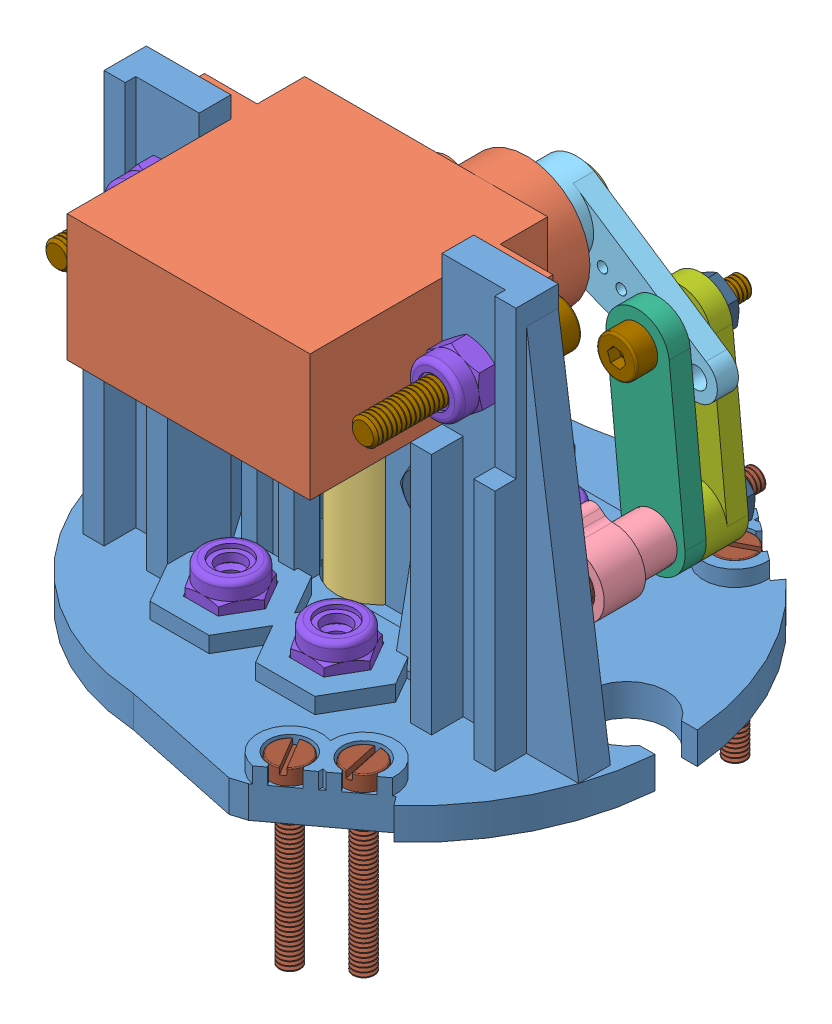
SolidWorks assembly Rückseite, configuration Standard. Lengths in mm.
Overall size (49.92 53 48.18).
28 component instances, 12 part files, 62 mates.
Components (placement in the parent):
- Backside-1: Backside [Standard] at (-0.7502 -6.4244 50) size (49.92 40 48.18)
- servo-1: servo [Standard] at (-9.7502 31.5756 70.5) x (1 0 0) z (0 1 0) size (33 29.25 12)
- Druecker-1: Druecker [Standard] at (-0.7502 16.2056 50) x (1 0 0) z (0 0 -1) size (7.5 32 7.5)
- Hebel-1: Hebel [Standard] at (9.2498 10.5756 50.9) x (0.999716 0.023826 0) z (0 0 -1) size (27.06 14 7.65)
- Servo-Arm-1: Servo-Arm [Standard] at (7.2498 25.5756 39.25) x (0.887861 -0.460111 0) z (-0.460111 -0.887861 0) size (20.6 4.3 7.2)
- Hebel2-1: Hebel2 [Standard] at (18.5142 5.5894 41.25) x (-0.099863 0.995001 0) z (0.995001 0.099863 0) size (21 2 6)
- Hebel2-Double-1: Hebel2-Double [Standard] at (18.5142 5.5894 39.25) x (-0.099863 0.995001 0) z (-0.995001 -0.099863 0) size (21 4 6)
- User Library-Mutter DIN-985_-1: User Library-Mutter DIN-985_ [Mutter DIN-985 M3-A2] at (-4.7502 -3.4244 60) x (0 1 0) z (0 0 1) size (4 6.35 5.5)
- User Library-Mutter DIN-985_-2: User Library-Mutter DIN-985_ [Mutter DIN-985 M3-A2] at (5.2498 -3.4244 60) x (0 1 0) z (-0.866025 0 0.5) size (4 6.35 5.5)
- User Library-Mutter DIN-985_-3: User Library-Mutter DIN-985_ [Mutter DIN-985 M3-A2] at (5.2498 -3.4244 40) x (0 1 0) z (-0.866025 0 -0.5) size (4 6.35 5.5)
- User Library-Mutter DIN-985_-4: User Library-Mutter DIN-985_ [Mutter DIN-985 M3-A2] at (-4.7502 -3.4244 40) x (0 1 0) z (-0.866025 0 0.5) size (4 6.35 5.5)
- socket head cap screw 4762_din-1: socket head cap screw 4762_din [ISO 4762 M2 x 10 --- 10S] at (9.2498 10.5756 43.8) x (0 0 1) z (0.327477 -0.944859 0) size (12 3.8 3.8)
- socket head cap screw 4762_din-2: socket head cap screw 4762_din [ISO 4762 M2 x 10 --- 10S] at (-0.7502 12.2056 55.25) x (0 0 -1) z (0.060223 0.998185 0) size (12 3.8 3.8)
- socket head cap screw 4762_din-3: socket head cap screw 4762_din [ISO 4762 M2 x 10 --- 10S] at (17.0163 20.5144 45.25) x (0 0 -1) z (0.77119 -0.636606 0) size (12 3.8 3.8)
- nut__style_1__m2x0_4__ansi_b18_2_4_1m-1: nut__style_1__m2x0_4__ansi_b18_2_4_1m [Default] at (-0.7502 12.2056 46.75) x (0.866025 -0.5 0) z (0 0 -1) size (4.62 4 1.6)
- nut__style_1__m2x0_4__ansi_b18_2_4_1m-2: nut__style_1__m2x0_4__ansi_b18_2_4_1m [Default] at (17.0163 20.5144 35.65) x (-0.849495 0.527596 0) z (0 0 1) size (4.62 4 1.6)
- nut__style_1__m2x0_4__ansi_b18_2_4_1m-3: nut__style_1__m2x0_4__ansi_b18_2_4_1m [Default] at (9.2498 10.5756 54.2) x (0.532315 -0.846547 0) z (0 0 1) size (4.62 4 1.6)
- User Library-Mutter DIN-985_-5: User Library-Mutter DIN-985_ [Mutter DIN-985 M2,5-A2] at (-12.7502 25.5756 58) x (0 0 1) z (-0.937505 -0.347973 0) size (3.8 5.77 5)
- User Library-Mutter DIN-985_-6: User Library-Mutter DIN-985_ [Mutter DIN-985 M2,5-A2] at (16.2498 25.5756 58) x (0 0 1) z (-0.395566 -0.918438 0) size (3.8 5.77 5)
- slotted cheese head screw_din-1: slotted cheese head screw_din [ISO 1207 - M2 x 16 --- 16S] at (11.3929 -2.0244 70.5635) x (0 -1 0) z (0.511563 0 0.859246) size (17.41 3.8 3.8)
- slotted cheese head screw_din-2: slotted cheese head screw_din [ISO 1207 - M2 x 16 --- 16S] at (11.3929 -2.0244 29.4365) x (0 -1 0) z (-0.876101 0 0.482128) size (17.41 3.8 3.8)
- slotted cheese head screw_din-3: slotted cheese head screw_din [ISO 1207 - M2 x 16 --- 16S] at (15.4084 -2.0244 32.4156) x (0 -1 0) z (-0.890448 0 0.455085) size (17.41 3.8 3.8)
- slotted cheese head screw_din-4: slotted cheese head screw_din [ISO 1207 - M2 x 16 --- 16S] at (15.4084 -2.0244 67.5844) x (0 -1 0) z (0.212665 0 0.977125) size (17.41 3.8 3.8)
- slotted cheese head screw_din-5: slotted cheese head screw_din [ISO 1207 - M2 x 16 --- 16S] at (18.5142 5.5894 50.85) x (0 0 -1) z (0.559209 -0.829027 0) size (17.41 3.8 3.8)
- nut__style_1__m2x0_4__ansi_b18_2_4_1m-4: nut__style_1__m2x0_4__ansi_b18_2_4_1m [Default] at (18.5142 5.5894 37.25) x (-0.800931 0.598757 0) z (0 0 -1) size (4.62 4 1.6)
- cross fh tapping 7976_din-2: cross fh tapping 7976_din [Tapping screw DIN 7982-ST2.9x6.5-C-Z-S] at (7.2498 25.5756 38.5) x (0 0 1) z (-0.95506 0.296413 0) size (6.51 5.5 5.5)
- socket head cap screw 4762_din-4: socket head cap screw 4762_din [ISO 4762 M2.5 x 16 --- 16S] at (-12.7502 25.5756 50) x (0 0 1) z (0.225641 0.974211 0) size (18.5 4.5 4.5)
- socket head cap screw 4762_din-5: socket head cap screw 4762_din [ISO 4762 M2.5 x 16 --- 16S] at (16.2498 25.5756 50) x (0 0 1) z (-0.799016 -0.60131 0) size (18.5 4.5 4.5)
Mates (geometry in assembly coordinates):
- Konzentrisch1: concentric anti-aligned: cylinder of Druecker-1 through (-0.7502 -15.7944 50) axis (0 1 0) radius 3.75; cylinder of Backside-1 through (-0.7502 -3.4244 50) axis (0 -1 0) radius 4
- Konzentrisch2: concentric aligned: cylinder of Backside-1 through (9.2498 10.5756 57.5) axis (0 0 1) radius 1.15; cylinder of Hebel-1 through (9.2498 10.5756 49) axis (0 0 1) radius 1.15
- Deckungsgleich1: coincident anti-aligned: plane of Hebel-1 through (9.2498 10.5756 49) normal (0 0 -1); plane of Backside-1 through (6.7498 13.5756 49) normal (0 0 1)
- Parallel1: parallel anti-aligned: plane of Druecker-1 through (-5.7502 8.2056 51) normal (0 0 -1); plane of Hebel-1 through (9.2498 10.5756 50.9) normal (0 0 1)
- Langloch1: slot anti-aligned: cylinder of Druecker-1 through (-0.7502 12.2056 54) axis (0 0 -1) radius 1.1; cylinder of Hebel-1 through (0.346 11.7238 49) axis (0 0 1) radius 1.15; cylinder of Hebel-1 through (-3.1704 13.6303 49) axis (0 0 1) radius 1.15
- Konzentrisch3: concentric anti-aligned: cylinder of servo-1 through (7.2498 25.5756 44) axis (0 0 1) radius 6; cylinder of Servo-Arm-1 through (7.2498 25.5756 43.55) axis (0 0 -1) radius 2.25
- Deckungsgleich6: coincident anti-aligned: plane of Backside-1 through (-9.7502 31.5756 58) normal (1 0 0); plane of servo-1 through (-9.7502 31.5756 48) normal (-1 0 0)
- Deckungsgleich7: coincident anti-aligned: plane of servo-1 through (18.2498 31.5756 55) normal (0 0 1); plane of Backside-1 through (-17.7502 19.5756 55) normal (0 0 -1)
- Deckungsgleich9: coincident anti-aligned: plane of Hebel2-1 through (18.5142 5.5894 41.25) normal (0 0 -1); plane of Servo-Arm-1 through (7.2498 25.5756 41.25) normal (0 0 1)
- Konzentrisch4: concentric anti-aligned: cylinder of Hebel-1 through (18.5142 5.5894 47) axis (0 0 1) radius 1.15; cylinder of Hebel2-1 through (18.5142 5.5894 43.25) axis (0 0 -1) radius 1.15
- Deckungsgleich12: coincident anti-aligned: plane of servo-1 through (7.2498 25.5756 41.25) normal (0 0 -1); plane of Servo-Arm-1 through (7.2498 25.5756 41.25) normal (0 0 1)
- Konzentrisch5: concentric aligned: cylinder of Servo-Arm-1 through (17.0163 20.5144 41.25) axis (0 0 -1) radius 0.5; cylinder of Hebel2-1 through (17.0163 20.5144 43.25) axis (0 0 -1) radius 1.15
- Deckungsgleich28: coincident anti-aligned: plane of Backside-1 through (-0.7502 -3.4244 50) normal (0 1 0); plane of User Library-Mutter DIN-985_-1 through (-7.4789 -3.4244 60) normal (0 -1 0)
- Deckungsgleich29: coincident anti-aligned: plane of Backside-1 through (-0.7502 -3.4244 50) normal (0 1 0); plane of User Library-Mutter DIN-985_-2 through (3.8855 -3.4244 57.6369) normal (0 -1 0)
- Deckungsgleich31: coincident anti-aligned: plane of Backside-1 through (-0.7502 -3.4244 50) normal (0 1 0); plane of User Library-Mutter DIN-985_-3 through (6.6142 -3.4244 37.6369) normal (0 -1 0)
- Deckungsgleich30: coincident anti-aligned: plane of Backside-1 through (-0.7502 -3.4244 50) normal (0 1 0); plane of User Library-Mutter DIN-985_-4 through (-6.1145 -3.4244 37.6369) normal (0 -1 0)
- Deckungsgleich21: coincident anti-aligned: plane of Backside-1 through (9.2498 10.5756 45.8) normal (0 0 -1); plane of socket head cap screw 4762_din-1 through (7.4546 9.9534 45.8) normal (0 0 1)
- Konzentrisch20: concentric anti-aligned: cylinder of Backside-1 through (9.2498 10.5756 57.5) axis (0 0 1) radius 1.15; cylinder of socket head cap screw 4762_din-1 through (9.2498 10.5756 12.05) axis (0 0 -1) radius 1
- Konzentrisch19: concentric anti-aligned: cylinder of Druecker-1 through (-0.7502 12.2056 54) axis (0 0 -1) radius 1.1; cylinder of socket head cap screw 4762_din-2 through (-0.7502 12.2056 87) axis (0 0 1) radius 1
- Deckungsgleich38: coincident anti-aligned: plane of Hebel2-1 through (18.5142 5.5894 43.25) normal (0 0 1); plane of socket head cap screw 4762_din-3 through (18.2258 21.9797 43.25) normal (0 0 -1)
- Konzentrisch38: concentric anti-aligned: cylinder of Hebel2-1 through (17.0163 20.5144 43.25) axis (0 0 -1) radius 1.15; cylinder of socket head cap screw 4762_din-3 through (17.0163 20.5144 77) axis (0 0 1) radius 1
- Deckungsgleich41: coincident anti-aligned: plane of Druecker-1 through (-0.7502 16.2056 46.75) normal (0 0 -1); plane of nut__style_1__m2x0_4__ansi_b18_2_4_1m-1 through (1.2503 11.0506 46.75) normal (0 0 1)
- Konzentrisch49: concentric aligned: circle of socket head cap screw 4762_din-2; circle of nut__style_1__m2x0_4__ansi_b18_2_4_1m-1
- Konzentrisch50: concentric anti-aligned: circle of socket head cap screw 4762_din-3; circle of nut__style_1__m2x0_4__ansi_b18_2_4_1m-2
- Deckungsgleich33: coincident anti-aligned: plane of Backside-1 through (9.2498 10.5756 54.2) normal (0 0 1); plane of nut__style_1__m2x0_4__ansi_b18_2_4_1m-3 through (10.4795 8.6201 54.2) normal (0 0 -1)
- Konzentrisch48: concentric aligned: circle of socket head cap screw 4762_din-1; circle of nut__style_1__m2x0_4__ansi_b18_2_4_1m-3
- Deckungsgleich36: coincident anti-aligned: plane of Backside-1 through (-11.7502 31.5756 58) normal (0 0 1); plane of User Library-Mutter DIN-985_-5 through (-13.5593 27.7554 58) normal (0 0 -1)
- Deckungsgleich37: coincident anti-aligned: plane of Backside-1 through (15.2498 31.5756 58) normal (0 0 1); plane of User Library-Mutter DIN-985_-6 through (14.1143 26.4954 58) normal (0 0 -1)
- Konzentrisch51: concentric aligned: circle of Backside-1; circle of User Library-Mutter DIN-985_-1
- Konzentrisch52: concentric aligned: circle of Backside-1; circle of User Library-Mutter DIN-985_-2
- Konzentrisch53: concentric aligned: circle of Backside-1; circle of User Library-Mutter DIN-985_-4
- Konzentrisch54: concentric aligned: circle of Backside-1; circle of User Library-Mutter DIN-985_-3
- Konzentrisch55: concentric aligned: circle of User Library-Mutter DIN-985_-5; cylinder of Backside-1 through (-12.7502 25.5756 41) axis (0 0 1) radius 1.25
- Konzentrisch56: concentric aligned: circle of User Library-Mutter DIN-985_-6; cylinder of Backside-1 through (16.2498 25.5756 41) axis (0 0 1) radius 1.25
- Deckungsgleich40: coincident anti-aligned: plane of Druecker-1 through (-0.7502 12.2056 53.25) normal (0 0 1); plane of socket head cap screw 4762_din-2 through (-2.6467 12.32 53.25) normal (0 0 -1)
- Konzentrisch59: concentric aligned: cylinder of Backside-1 through (15.4084 -13.4244 32.4156) axis (0 1 0) radius 1.1; cylinder of slotted cheese head screw_din-3 through (15.4084 23.3756 32.4156) axis (0 1 0) radius 1
- Konzentrisch60: concentric aligned: cylinder of Backside-1 through (11.3929 -13.4244 29.4365) axis (0 1 0) radius 1.1; cylinder of slotted cheese head screw_din-2 through (11.3929 23.3756 29.4365) axis (0 1 0) radius 1
- Konzentrisch61: concentric aligned: cylinder of Backside-1 through (15.4084 -13.4244 67.5844) axis (0 1 0) radius 1.1; cylinder of slotted cheese head screw_din-4 through (15.4084 23.3756 67.5844) axis (0 1 0) radius 1
- Konzentrisch62: concentric aligned: cylinder of Backside-1 through (11.3929 -13.4244 70.5635) axis (0 1 0) radius 1.1; cylinder of slotted cheese head screw_din-1 through (11.3929 23.3756 70.5635) axis (0 1 0) radius 1
- Deckungsgleich42: coincident anti-aligned: plane of Backside-1 through (-0.7502 -3.4244 50) normal (0 1 0); plane of slotted cheese head screw_din-3 through (15.8635 -3.4244 33.306) normal (0 -1 0)
- Deckungsgleich43: coincident anti-aligned: plane of Backside-1 through (-0.7502 -3.4244 50) normal (0 1 0); plane of slotted cheese head screw_din-2 through (11.875 -3.4244 30.3126) normal (0 -1 0)
- Deckungsgleich44: coincident anti-aligned: plane of Backside-1 through (-0.7502 -3.4244 50) normal (0 1 0); plane of slotted cheese head screw_din-1 through (12.2521 -3.4244 70.052) normal (0 -1 0)
- Deckungsgleich45: coincident anti-aligned: plane of Backside-1 through (-0.7502 -3.4244 50) normal (0 1 0); plane of slotted cheese head screw_din-4 through (16.3856 -3.4244 67.3717) normal (0 -1 0)
- Konzentrisch64: concentric aligned: cylinder of Hebel-1 through (18.5142 5.5894 47) axis (0 0 1) radius 1.15; cylinder of slotted cheese head screw_din-5 through (18.5142 5.5894 76.25) axis (0 0 1) radius 1
- Deckungsgleich47: coincident aligned: circle of Hebel-1; plane of slotted cheese head screw_din-5 through (19.3433 6.1486 49.45) normal (0 0 -1)
- Konzentrisch65: concentric anti-aligned: cylinder of Hebel2-1 through (18.5142 5.5894 43.25) axis (0 0 -1) radius 1.15; cylinder of nut__style_1__m2x0_4__ansi_b18_2_4_1m-4 through (18.5142 5.5894 37.25) axis (0 0 1) radius 0.7835
- Deckungsgleich50: coincident: circle of Servo-Arm-1; cone of cross fh tapping 7976_din-2 through (7.2498 25.5756 40.2) axis (0 0 1)
- Parallel2: parallel anti-aligned: plane of Backside-1 through (10.5481 -1.9244 43.4769) normal (-0.866025 0 0.5); plane of User Library-Mutter DIN-985_-3 through (8.4252 0.5766 40) normal (0.866025 0 -0.5)
- Parallel3: parallel anti-aligned: plane of Backside-1 through (3.0481 -1.9244 47.8071) normal (-0.866025 0 0.5); plane of User Library-Mutter DIN-985_-4 through (-1.5748 0.5766 40) normal (0.866025 0 -0.5)
- Parallel4: parallel anti-aligned: plane of Backside-1 through (3.0481 -1.9244 52.1929) normal (-0.866025 0 -0.5); plane of User Library-Mutter DIN-985_-1 through (-3.1625 0.5766 62.75) normal (0.866025 0 0.5)
- Parallel5: parallel anti-aligned: plane of Backside-1 through (10.5481 -1.9244 56.5231) normal (-0.866025 0 -0.5); plane of User Library-Mutter DIN-985_-2 through (6.8375 0.5766 62.75) normal (0.866025 0 0.5)
- Parallel6: parallel anti-aligned: plane of Druecker-1 through (-2.8002 13.3892 46.75) normal (0.5 -0.866025 0); plane of nut__style_1__m2x0_4__ansi_b18_2_4_1m-1 through (-2.7507 13.3606 45.15) normal (-0.5 0.866025 0)
- Deckungsgleich51: coincident anti-aligned: plane of Backside-1 through (-0.7502 19.5756 50) normal (0 1 0); plane of servo-1 through (-9.7502 19.5756 48) normal (0 -1 0)
- Konzentrisch66: concentric anti-aligned: circle of socket head cap screw 4762_din-4; circle of User Library-Mutter DIN-985_-5
- Konzentrisch67: concentric anti-aligned: circle of socket head cap screw 4762_din-5; circle of User Library-Mutter DIN-985_-6
- Deckungsgleich52: coincident anti-aligned: plane of servo-1 through (18.2498 31.5756 52.5) normal (0 0 -1); plane of socket head cap screw 4762_din-5 through (14.8969 27.3734 52.5) normal (0 0 1)
- Deckungsgleich53: coincident anti-aligned: plane of servo-1 through (18.2498 31.5756 52.5) normal (0 0 -1); plane of socket head cap screw 4762_din-4 through (-10.5582 25.0679 52.5) normal (0 0 1)
- Konzentrisch68: concentric aligned: circle of Servo-Arm-1; cylinder of Hebel2-Double-1 through (17.0163 20.5144 37.25) axis (0 0 1) radius 1.15
- Konzentrisch69: concentric anti-aligned: circle of Hebel2-1; circle of Hebel2-Double-1
- Deckungsgleich55: coincident anti-aligned: plane of Servo-Arm-1 through (7.2498 25.5756 39.25) normal (0 0 -1); plane of Hebel2-Double-1 through (18.5142 5.5894 39.25) normal (0 0 1)
- Deckungsgleich56: coincident anti-aligned: plane of nut__style_1__m2x0_4__ansi_b18_2_4_1m-2 through (15.054 21.7332 37.25) normal (0 0 1); plane of Hebel2-Double-1 through (18.5142 5.5894 37.25) normal (0 0 -1)
- Deckungsgleich57: coincident anti-aligned: plane of nut__style_1__m2x0_4__ansi_b18_2_4_1m-4 through (16.6641 6.9725 37.25) normal (0 0 1); plane of Hebel2-Double-1 through (18.5142 5.5894 37.25) normal (0 0 -1)
